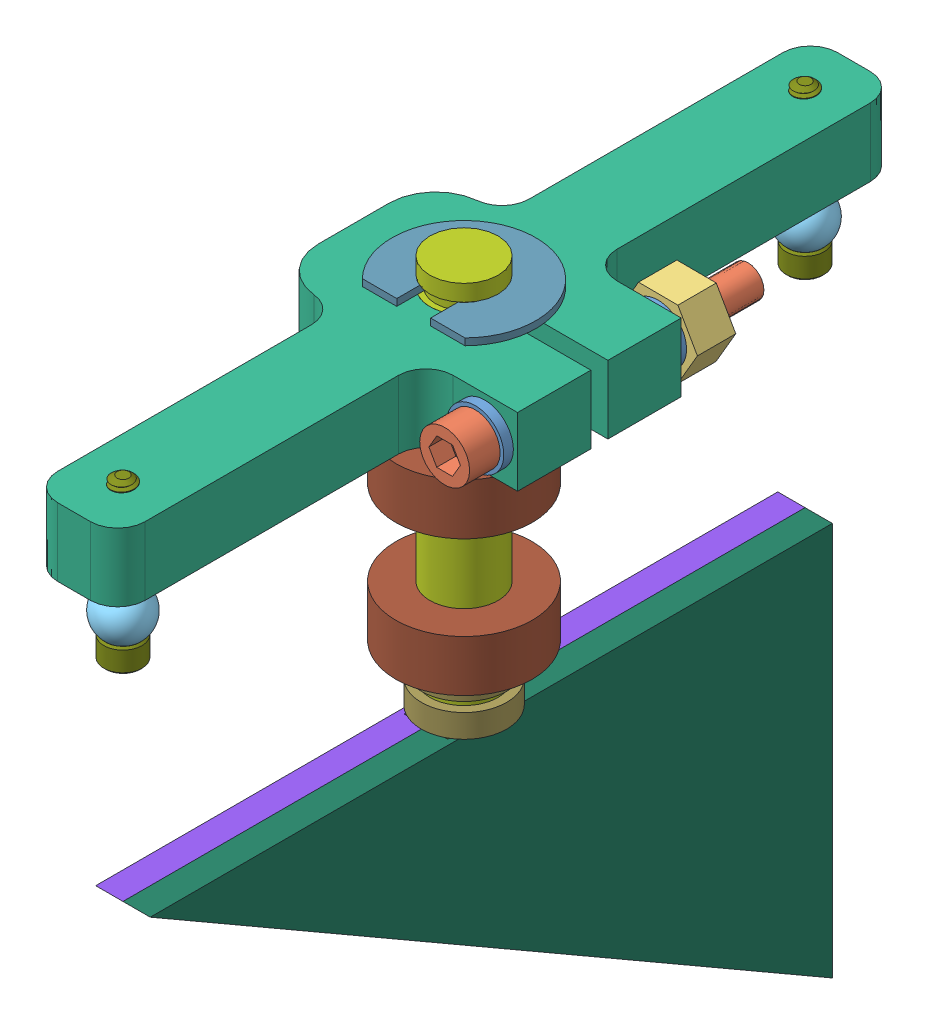
SolidWorks assembly ControlArmWithBall, configuration Default. Lengths in mm.
Overall size (38.79 72.85 74.4).
23 component instances, 17 part files, 51 mates.
Components (placement in the parent):
- 4-40_Washer_MC-90945A711-1: 4-40_Washer_MC-90945A711 [Default] at (11.6137 -3.175 -2.577) x (0.999989 -0.004774 0) z (0 0 1) size (5.31 5.31 0.89)
- 4-40_1.0_Socket_Head_Cap_Screw_MC- 92196A115-1: 4-40_1.0_Socket_Head_Cap_Screw_MC- 92196A115 [Default] at (11.6137 -3.175 -10.959) x (0.999989 -0.004774 0) z (0 0 1) size (4.65 4.65 28.24)
- 4-40_Washer_MC-90945A711-2: 4-40_Washer_MC-90945A711 [Default] at (11.6137 -3.175 13.552) x (0.999989 -0.004774 0) z (0 0 1) size (5.31 5.31 0.89)
- 4-40_Lock_Nut_MC-91831A005-1: 4-40_Lock_Nut_MC-91831A005 [Default] at (11.6137 -3.175 -6.1488) x (0.999989 -0.004774 0) z (0 0 1) size (7.33 6.35 3.57)
- 2-56_Ball_Joint_Base-1: 2-56_Ball_Joint_Base [Default] at (2.0592 -6.35 37.682) x (1 0 0) z (0 -1 0) size (4.78 4.78 2.03)
- 2-56_Ball_Joint_Half_Sphere-1: 2-56_Ball_Joint_Half_Sphere [Default] at (2.0592 -10.1727 37.682) x (-0.613448 0 -0.789735) z (0.789735 0 -0.613448) size (4.78 3.58 4.78)
- 2-56_Ball_Joint_Base-2: 2-56_Ball_Joint_Base [Default] at (2.0592 -6.35 -25.818) x (-0.837169 0 -0.546944) z (0 -1 0) size (4.78 4.78 2.03)
- 2-56_Ball_Joint_Half_Sphere-2: 2-56_Ball_Joint_Half_Sphere [Default] at (2.0592 -10.1727 -25.818) x (0.626045 0 0.779787) z (0.779787 0 -0.626045) size (4.78 3.58 4.78)
- ControlArm-1: ControlArm [Default] at (-6.8308 0 5.932) x (-1 0 0) z (0 -1 0) size (22.86 74.4 10.16)
- Shaft-1: Shaft [Default] at (2.0592 0 5.932) x (0 0 1) z (0 -1 0) size (6.35 6.35 45.47)
- Canard_Half-1: Canard_Half [Default] at (2.0592 -33.655 -25.818) x (0 -1 0) z (-1 0 0) size (36.65 63.5 2.54)
- Canard_Shaft_Plate-1: Canard_Shaft_Plate [Default] at (2.0592 -46.609 5.932) x (0 0 1) z (1 0 0) size (19.05 13.54 1.57)
- ControlArm_Spacer-1: ControlArm_Spacer [Default] at (2.0592 -11.049 5.932) x (1 0 0) z (0 1 0) size (7.94 7.94 4.7)
- 0.5in_Ball_Berring_MC-57155K376-1: 0.5in_Ball_Berring_MC-57155K376 [Default] at (2.0592 -15.8115 5.932) x (1 0 0) z (0 1 0) size (12.7 12.7 4.76)
- 0.5in_Ball_Berring_MC-57155K376-2: 0.5in_Ball_Berring_MC-57155K376 [Default] at (2.0592 -28.448 5.932) x (1 0 0) z (0 1 0) size (12.7 12.7 4.76)
- Canard_Spacer-1: Canard_Spacer [Default] at (2.0592 -33.655 5.932) x (1 0 0) z (0 1 0) size (7.94 7.94 2.16)
- 05in_bearing_Spacer_MC-9056K653--1: 05in_bearing_Spacer_MC-9056K653- [Default] at (1.8198 -23.6855 6.0098) x (1 0 0) z (0 1 0) (suppressed, hidden)
- 0.25x0.0625_Woodruf_Key_MC-98525A050-1: 0.25x0.0625_Woodruf_Key_MC-98525A050 [Default] at (-2.3858 -3.175 5.1383) x (0 1 0) z (0 0 1) size (6.31 2.82 1.59)
- E-Clip_MC-97431A300-1: E-Clip_MC-97431A300 [Default] at (2.0592 0 5.932) x (1 0 0) z (0 1 0) size (13.39 11.38 0.64)
- Canard_Spacer-2: Canard_Spacer [Default] at (2.0592 -30.607 5.932) x (1 0 0) z (0 1 0) size (7.94 7.94 2.16)
- Canard_Half2-1: Canard_Half2 [Default] at (2.0592 -33.655 -25.818) x (0 -1 0) z (-1 0 0) size (36.65 63.5 2.54)
- 2-56_0.5in_Allen_Head_Cap_Screw_2_MC-92196A081-1: 2-56_0.5in_Allen_Head_Cap_Screw_2_MC-92196A081 [92196A081] at (2.0592 0.7366 37.682) x (1 0 0) z (0 1 0) size (3.56 3.56 15.4)
- 2-56_0.5in_Allen_Head_Cap_Screw_2_MC-92196A081-2: 2-56_0.5in_Allen_Head_Cap_Screw_2_MC-92196A081 [92196A081] at (2.0592 0.7366 -25.818) x (1 0 0) z (0 1 0) size (3.56 3.56 15.4)
Mates (geometry in assembly coordinates):
- Coincident5: coincident anti-aligned: axis of ControlArm-1 through (2.0592 0 5.932) axis (0 -1 0); axis of Shaft-1 through (2.0592 1.016 5.932) axis (0 1 0)
- Perpendicular1: perpendicular: line of Shaft-1 through (2.0592 0 5.932) axis (-1 0 0); line of ControlArm-1 through (14.6617 0 6.7258) axis (0 0 1)
- Parallel4: parallel aligned: line of Shaft-1 through (-1.015 -6.0388 5.1383) axis (0 1 0); line of 0.25x0.0625_Woodruf_Key_MC-98525A050-1 through (-2.0306 -6.3301 5.1383) axis (0 1 0)
- Coincident14: coincident aligned: axis of 2-56_Ball_Joint_Base-1 through (2.0592 -7.62 37.682) axis (0 1 0); axis of 2-56_Ball_Joint_Half_Sphere-1 through (2.0592 -11.7015 37.682) axis (0 1 0)
- Distance2: distance = 0 mm anti-aligned: plane of 2-56_Ball_Joint_Base-1 through (2.0592 -8.382 37.682) normal (0 -1 0); plane of 2-56_Ball_Joint_Half_Sphere-1 through (2.0592 -8.382 37.682) normal (0 1 0)
- Coincident23: coincident anti-aligned: axis of Shaft-1 through (2.0592 1.016 5.932) axis (0 1 0); axis of 0.5in_Ball_Berring_MC-57155K376-1 through (2.0592 -11.049 5.932) axis (0 -1 0)
- Coincident25: coincident anti-aligned: axis of Shaft-1 through (2.0592 1.016 5.932) axis (0 1 0); axis of 0.5in_Ball_Berring_MC-57155K376-2 through (2.0592 -23.6855 5.932) axis (0 -1 0)
- Coincident27: coincident anti-aligned: plane of ControlArm-1 through (-8.1983 -6.35 -1.688) normal (0 -1 0); plane of 2-56_Ball_Joint_Base-1 through (2.0592 -6.35 37.682) normal (0 1 0)
- Coincident28: coincident aligned: axis of 2-56_Ball_Joint_Base-1 through (2.0592 -7.62 37.682) axis (0 1 0); axis of ControlArm-1 through (2.0592 -6.35 37.682) axis (0 1 0)
- Coincident29: coincident anti-aligned: axis of 2-56_Ball_Joint_Base-2 through (2.0592 -7.62 -25.818) axis (0 1 0); axis of 2-56_Ball_Joint_Half_Sphere-2 through (2.0592 -8.6439 -25.818) axis (0 -1 0)
- Coincident30: coincident anti-aligned: circle of 2-56_Ball_Joint_Base-2; plane of 2-56_Ball_Joint_Half_Sphere-2 through (2.0592 -8.382 -25.818) normal (0 1 0)
- Coincident31: coincident aligned: axis of 2-56_Ball_Joint_Base-2 through (2.0592 -7.62 -25.818) axis (0 1 0); axis of ControlArm-1 through (2.0592 -6.35 -25.818) axis (0 1 0)
- Coincident32: coincident anti-aligned: plane of 2-56_Ball_Joint_Base-2 through (2.0592 -6.35 -25.818) normal (0 1 0); plane of ControlArm-1 through (-8.1983 -6.35 -1.688) normal (0 -1 0)
- Coincident33: coincident anti-aligned: axis of Shaft-1 through (2.0592 1.016 5.932) axis (0 1 0); axis of Canard_Spacer-1 through (2.0592 -31.496 5.932) axis (0 -1 0)
- Coincident34: coincident aligned: plane of Canard_Spacer-1 through (2.0592 -33.655 5.932) normal (0 -1 0); plane of Shaft-1 through (0.1542 -33.655 2.757) normal (0 -1 0)
- Coincident36: coincident anti-aligned: plane of ControlArm-1 through (14.6617 -6.35 -1.688) normal (0 0 -1); plane of 4-40_Washer_MC-90945A711-1 through (11.6137 -3.175 -1.688) normal (0 0 1)
- Coincident37: coincident anti-aligned: axis of 4-40_Washer_MC-90945A711-1 through (11.6137 -3.175 -1.688) axis (0 0 -1); axis of ControlArm-1 through (11.6137 -3.175 -1.688) axis (0 0 1)
- Coincident38: coincident anti-aligned: axis of 4-40_1.0_Socket_Head_Cap_Screw_MC- 92196A115-1 through (11.6137 -3.175 14.441) axis (0 0 -1); axis of ControlArm-1 through (11.6137 -3.175 -1.688) axis (0 0 1)
- Coincident39: coincident anti-aligned: plane of ControlArm-1 through (-0.5783 -6.35 13.552) normal (0 0 1); plane of 4-40_Washer_MC-90945A711-2 through (11.6137 -3.175 13.552) normal (0 0 -1)
- Coincident40: coincident aligned: axis of 4-40_1.0_Socket_Head_Cap_Screw_MC- 92196A115-1 through (11.6137 -3.175 14.441) axis (0 0 -1); axis of 4-40_Washer_MC-90945A711-2 through (11.6137 -3.175 14.441) axis (0 0 -1)
- Coincident41: coincident anti-aligned: plane of 4-40_1.0_Socket_Head_Cap_Screw_MC- 92196A115-1 through (11.6137 -3.175 14.441) normal (0 0 -1); plane of 4-40_Washer_MC-90945A711-2 through (11.6137 -3.175 14.441) normal (0 0 1)
- Coincident42: coincident anti-aligned: plane of 4-40_Washer_MC-90945A711-1 through (11.6137 -3.175 -2.577) normal (0 0 -1); plane of 4-40_Lock_Nut_MC-91831A005-1 through (15.2798 -3.1925 -2.577) normal (0 0 1)
- Coincident43: coincident aligned: axis of 4-40_1.0_Socket_Head_Cap_Screw_MC- 92196A115-1 through (11.6137 -3.175 14.441) axis (0 0 -1); axis of 4-40_Lock_Nut_MC-91831A005-1 through (11.6137 -3.175 -2.577) axis (0 0 -1)
- Coincident48: coincident anti-aligned: axis of Shaft-1 through (1.8198 1.016 6.0098) axis (0 1 0); axis of 05in_bearing_Spacer_MC-9056K653--1 through (1.8198 -15.8115 6.0098) axis (0 -1 0)
- Coincident49: coincident anti-aligned: plane of 0.5in_Ball_Berring_MC-57155K376-1 through (1.8198 -15.8115 6.0098) normal (0 -1 0); plane of 05in_bearing_Spacer_MC-9056K653--1 through (1.8198 -15.8115 6.0098) normal (0 1 0)
- Coincident50: coincident anti-aligned: plane of 0.5in_Ball_Berring_MC-57155K376-2 through (1.8198 -23.6855 6.0098) normal (0 1 0); plane of 05in_bearing_Spacer_MC-9056K653--1 through (1.8198 -23.6855 6.0098) normal (0 -1 0)
- Coincident51: coincident anti-aligned: plane of Shaft-1 through (-2.3858 -3.175 6.7258) normal (0 0 -1); plane of 0.25x0.0625_Woodruf_Key_MC-98525A050-1 through (-2.3858 -3.175 6.7258) normal (0 0 1)
- Coincident52: coincident anti-aligned: axis of Shaft-1 through (2.0592 1.016 5.932) axis (0 1 0); axis of E-Clip_MC-97431A300-1 through (2.0592 0.635 5.932) axis (0 -1 0)
- Coincident53: coincident anti-aligned: plane of Shaft-1 through (2.0592 0 5.932) normal (0 1 0); plane of E-Clip_MC-97431A300-1 through (2.0592 0 5.932) normal (0 -1 0)
- Coincident54: coincident anti-aligned: axis of Shaft-1 through (2.0592 1.016 5.932) axis (0 1 0); axis of ControlArm_Spacer-1 through (2.0592 -6.35 5.932) axis (0 -1 0)
- Coincident55: coincident anti-aligned: plane of ControlArm-1 through (-8.1983 -6.35 -1.688) normal (0 -1 0); plane of ControlArm_Spacer-1 through (2.0592 -6.35 5.932) normal (0 1 0)
- Coincident56: coincident anti-aligned: plane of 0.5in_Ball_Berring_MC-57155K376-1 through (2.0592 -11.049 5.932) normal (0 1 0); plane of ControlArm_Spacer-1 through (2.0592 -11.049 5.932) normal (0 -1 0)
- Coincident57: coincident aligned: plane of ControlArm-1 through (-8.1983 0 -1.688) normal (0 1 0); plane of Shaft-1 through (2.0592 0 5.932) normal (0 1 0)
- Concentric1: concentric aligned: cylinder of Shaft-1 through (-2.3858 -3.175 6.7258) axis (0 0 -1) radius 3.175; cylinder of 0.25x0.0625_Woodruf_Key_MC-98525A050-1 through (-2.3858 -3.175 6.7258) axis (0 0 -1) radius 3.175
- Coincident58: coincident anti-aligned: plane of Canard_Shaft_Plate-1 through (2.0592 -46.609 5.932) normal (1 0 0); plane of Shaft-1
- Coincident59: coincident: moEndPointRef_w of Shaft-1; line of Canard_Shaft_Plate-1 through (2.8466 -37.084 5.932) axis (-1 0 0)
- Coincident60: coincident anti-aligned: plane of Canard_Shaft_Plate-1 through (2.8466 -37.084 -3.593) normal (0 1 0); plane of Shaft-1 through (2.0592 -37.084 2.757) normal (0 -1 0)
- Coincident61: coincident aligned: plane of Canard_Half-1 through (2.0592 -33.655 -25.818) normal (-1 0 0); plane of Shaft-1
- Coincident63: coincident anti-aligned: plane of Shaft-1 through (0.1542 -33.655 2.757) normal (0 -1 0); plane of Canard_Half-1 through (-0.4808 -33.655 -25.818) normal (0 1 0)
- Coincident66: coincident aligned: line of Shaft-1 through (0.1542 -33.655 5.932) axis (-1 0 0); line of Canard_Half-1 through (2.0592 -33.655 5.932) axis (-1 0 0)
- Coincident67: coincident anti-aligned: axis of Shaft-1 through (2.0592 -42.926 5.932) axis (0 1 0); axis of Canard_Spacer-2 through (2.0592 -28.448 5.932) axis (0 -1 0)
- Coincident68: coincident anti-aligned: plane of 0.5in_Ball_Berring_MC-57155K376-2 through (2.0592 -28.448 5.932) normal (0 -1 0); plane of Canard_Spacer-2 through (2.0592 -28.448 5.932) normal (0 1 0)
- Parallel6: parallel anti-aligned: plane of Canard_Half-1 through (2.0592 -33.655 -25.818) normal (1 0 0); plane of Canard_Half2-1 through (2.0592 -33.655 -25.818) normal (-1 0 0)
- Coincident73: coincident aligned: line of Canard_Half-1 through (2.0592 -33.655 2.376) axis (0 0 -1); line of Canard_Half2-1 through (2.0592 -33.655 2.376) axis (0 0 -1)
- Coincident74: coincident: point of Canard_Half-1; point of Canard_Half2-1
- Coincident75: coincident aligned: axis of 2-56_Ball_Joint_Half_Sphere-1 through (2.0592 -11.7015 37.682) axis (0 1 0); axis of 2-56_0.5in_Allen_Head_Cap_Screw_2_MC-92196A081-1 through (2.0592 -13.97 37.682) axis (0 1 0)
- Coincident76: coincident anti-aligned: plane of 2-56_Ball_Joint_Half_Sphere-1 through (2.0592 -11.9634 37.682) normal (0 -1 0); plane of 2-56_0.5in_Allen_Head_Cap_Screw_2_MC-92196A081-1 through (2.0592 -11.9634 37.682) normal (0 1 0)
- Coincident77: coincident anti-aligned: axis of 2-56_Ball_Joint_Half_Sphere-2 through (2.0592 -8.6439 -25.818) axis (0 -1 0); axis of 2-56_0.5in_Allen_Head_Cap_Screw_2_MC-92196A081-2 through (2.0592 -13.97 -25.818) axis (0 1 0)
- Coincident78: coincident anti-aligned: plane of 2-56_Ball_Joint_Half_Sphere-2 through (2.0592 -11.9634 -25.818) normal (0 -1 0); plane of 2-56_0.5in_Allen_Head_Cap_Screw_2_MC-92196A081-2 through (2.0592 -11.9634 -25.818) normal (0 1 0)
- Coincident80: coincident aligned: plane of ControlArm-1 through (-8.1983 0 -1.688) normal (0 1 0); plane of assembly through (0 0 0) normal (0 1 0)
- Parallel7: parallel anti-aligned: plane of Canard_Half-1 through (-0.4808 -33.655 -25.818) normal (-1 0 0); plane of assembly through (0 0 0) normal (1 0 0)
